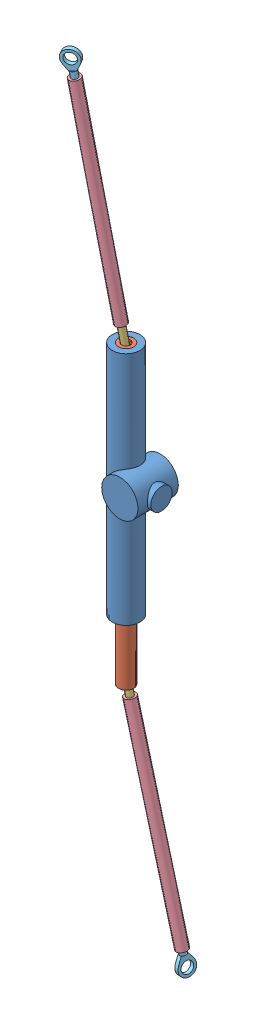
SolidWorks assembly Steering rack assembly (working), configuration Default. Lengths in mm.
Overall size (122.03 1184.94 95.86).
8 component instances, 5 part files, 16 mates.
Components (placement in the parent):
- Steering rack-1: Steering rack [Default] at origin size (73.3 350 60)
- l rod-1: l rod [Default] at (-20.65 -265 30) x (-0.255267 0 0.966871) z (0 1 0) size (22.59 22.59 440)
- ball-2: ball [Default] at (-19.4754 -262.8794 29.3565) x (0.626615 0.16614 -0.761414) z (0.76343 0.065481 0.642562) size (15 60 15)
- ball-3: ball [Default] at (-21.4833 172.9124 30.7825) x (0.590527 -0.018784 0.806799) z (0.799333 0.151246 -0.581542) size (15 60 15)
- s rod-2: s rod [Default] at (-60.0678 516.1458 67.015) x (-0.666953 -0.151976 0.729436) z (0.111102 -0.988318 -0.104329) size (16 16 320)
- s rod-3: s rod [Default] at (33.2065 -593.8541 0.493) x (0.763721 0.065557 0.642209) z (-0.156613 0.983926 0.085806) size (16 16 320)
- Part2-1: Part2 [Default] at (33.7575 -616.1231 -1.9205) x (-0.154635 -0.110234 0.981803) z (-0.156613 0.983926 0.085806) size (24 9.51 39.99)
- Part2-2: Part2 [Default] at (-64.3931 541.7381 67.087) x (0.866304 0.147756 -0.477164) z (0.111102 -0.988318 -0.104329) size (24 9.51 39.99)
Mates (geometry in assembly coordinates):
- Concentric1: concentric anti-aligned: cylinder of Steering rack-1 through (-20.65 -175 30) axis (0 1 0) radius 11.295; cylinder of l rod-1 through (-20.65 265 30) axis (0 -1 0) radius 11.295
- Tangent4: tangent anti-aligned: plane of l rod-1 through (-20.65 -158 30) normal (0 -1 0); sphere of ball-2
- Tangent5: tangent aligned: cylinder of l rod-1 through (-20.65 -158 30) axis (0 -1 0) radius 7.5; sphere of ball-2
- Tangent7: tangent anti-aligned: plane of l rod-1 through (-20.65 248 30) normal (0 1 0); sphere of ball-3
- Tangent8: tangent aligned: cylinder of l rod-1 through (-20.65 248 30) axis (0 1 0) radius 7.5; sphere of ball-3
- Concentric10: concentric aligned: cylinder of ball-3 through (-20.4375 259.9173 30.8319) axis (0.047219 0.981627 0.184874) radius 4.755; cylinder of s rod-2 through (-19.0072 289.6514 36.4319) axis (0.047219 0.981627 0.184874) radius 4.755
- Lock7: lock: unknown of ball-3; unknown of s rod-2
- Concentric12: concentric aligned: cylinder of ball-2 through (-19.9452 -169.9277 29.6139) axis (0.156613 -0.983926 -0.085806) radius 4.755; cylinder of s rod-3 through (-16.9098 -188.9979 27.9508) axis (0.156613 -0.983926 -0.085806) radius 4.755
- Lock8: lock: unknown of ball-2; unknown of s rod-3
- Concentric15: concentric aligned: cylinder of s rod-2 through (-19.0072 289.6514 36.4319) axis (0.047219 0.981627 0.184874) radius 4.755; cylinder of Part2-2 through (-4.0015 601.604 95.1833) axis (0.047219 0.981627 0.184874) radius 4.755
- Lock9: lock: unknown of s rod-2; unknown of Part2-2
- Concentric17: concentric aligned: cylinder of s rod-3 through (-16.9098 -188.9979 27.9508) axis (0.156613 -0.983926 -0.085806) radius 4.755; cylinder of Part2-1 through (32.3004 -498.1616 0.9895) axis (0.156613 -0.983926 -0.085806) radius 4.755
- Lock10: lock: unknown of s rod-3; unknown of Part2-1
- LimitDistance5: limit distance = 90 mm aligned: plane of l rod-1 through (-20.65 -265 30) normal (0 -1 0); plane of Steering rack-1 through (-20.65 -175 30) normal (0 -1 0)
- LimitAngle1: limit planar angle = 0.153004 rad aligned: cylinder of s rod-2 through (-24.5153 199.8841 33.6297) axis (-0.111102 0.988318 0.104329) radius 8; cylinder of l rod-1 through (-20.65 173 30) axis (0 1 0) radius 6.5
- LimitAngle3: limit planar angle = 0.179542 rad aligned: cylinder of ball-2 through (-19.9452 -259.9277 29.6139) axis (0.156613 -0.983926 -0.085806) radius 4.755; cylinder of l rod-1 through (-20.65 -263 30) axis (0 -1 0) radius 6.5
